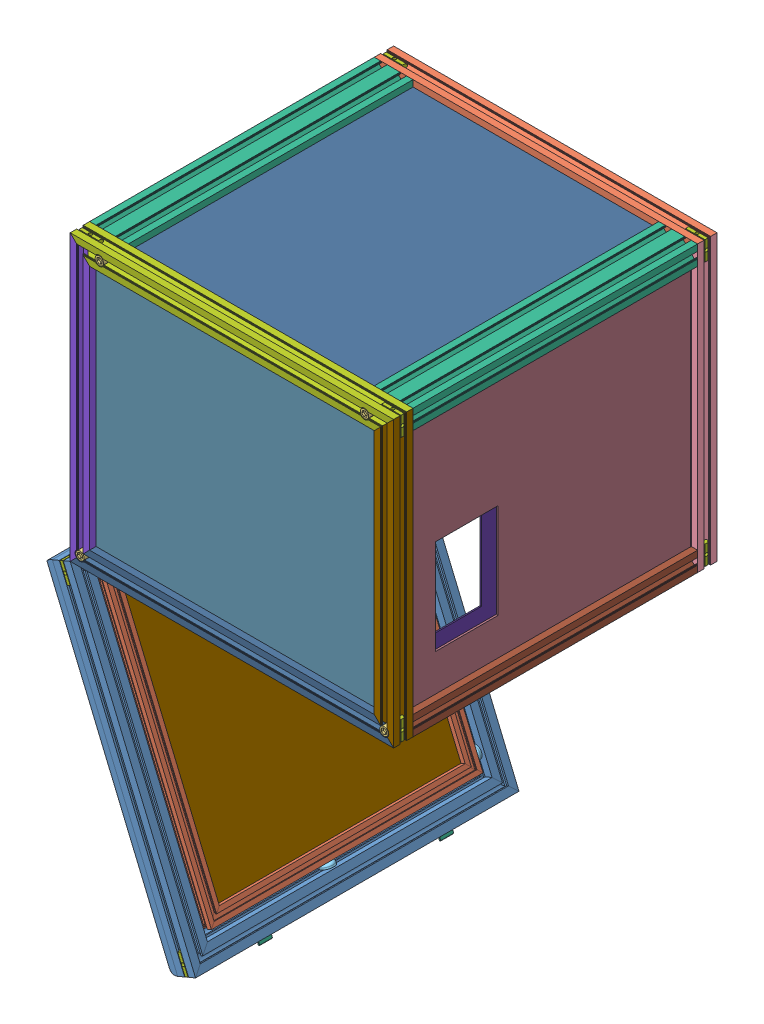
SolidWorks assembly 总装图, configuration 默认. Lengths in mm.
Overall size (555.31 924.17 500).
103 component instances, 37 part files, 0 mates.
Components (placement in the parent):
- Iner box-X3(JL-8-3060E) 500mm-1: Iner box-X3(JL-8-3060E) 500mm [默认] at (-176.4266 -29.8898 -15) x (0 1 0) z (1 0 0) size (60 30 500)
- Iner box-X4(JL-8-3060E) 500mm-1: Iner box-X4(JL-8-3060E) 500mm [默认] at (323.5734 410.1102 -15) x (0 -1 0) z (-1 0 0) size (60 30 500)
- Iner box-Y3(JL-8-3060E) 440mm-1: Iner box-Y3(JL-8-3060E) 440mm [默认] at (-176.4266 410.1102 -15) x (1 0 0) z (0 -1 0) size (60 30 440)
- Iner box-Y4(JL-8-3060E) 440mm-1: Iner box-Y4(JL-8-3060E) 440mm [默认] at (263.5734 410.1102 -15) x (1 0 0) z (0 -1 0) size (60 30 440)
- Iner box-Z1(JL-8-3030E) 440mm-1: Iner box-Z1(JL-8-3030E) 440mm [默认] at (-176.4266 -29.8898 15) size (30 30 440)
- Iner box-Z2(JL-8-6060E) 440mm-1: Iner box-Z2(JL-8-6060E) 440mm [默认] at (-116.4266 380.1102 455) x (-1 0 0) z (0 0 -1) size (60 30 440)
- Iner box-Z2(JL-8-6060E) 440mm-2: Iner box-Z2(JL-8-6060E) 440mm [默认] at (263.5734 380.1102 15) size (60 30 440)
- Iner box-X1(JL-8-3030E)-1: Iner box-X1(JL-8-3030E) [默认] at (-176.4266 410.1102 455) x (0 0 1) z (1 0 0) size (30 30 500)
- Iner box-Y1(JL-8-3030E) 440mm-1: Iner box-Y1(JL-8-3030E) 440mm [默认] at (-176.4266 -29.8898 455) x (0 0 1) z (0 1 0) size (30 30 440)
- Iner box-Y2(JL-8-3030E) 440mm-1: Iner box-Y2(JL-8-3030E) 440mm [默认] at (323.5734 410.1102 455) x (0 0 1) z (0 -1 0) size (30 30 440)
- Iner box-X2(JL-8-3030E)-1: Iner box-X2(JL-8-3030E) [默认] at (323.5734 -29.8898 455) x (0 0 1) z (-1 0 0) size (30 30 500)
- outer box-Z3(JL-8-3030E) 440mm-1: outer box-Z3(JL-8-3030E) 440mm [默认] at (323.5734 0.1102 15) x (-1 0 0) z (0 0 1) size (30 30 440)
- Iner box-X3(JL-6-2020E) 420mm-1: Iner box-X3(JL-6-2020E) 420mm [默认] at (-136.4266 370.1102 445) x (0 -1 0) z (1 0 0) size (20 20 420)
- Iner box-Y1(JL-6-2020E) 400mm-1: Iner box-Y1(JL-6-2020E) 400mm [默认] at (-136.4266 -29.8898 425) x (0 0 1) z (0 1 0) size (20 20 400)
- Iner box-Y2(JL-6-2020E) 400mm-1: Iner box-Y2(JL-6-2020E) 400mm [默认] at (263.5734 -29.8898 425) x (0 0 1) z (0 1 0) size (20 20 400)
- Iner box-X1(JL-6-2020E) 420mm-1: Iner box-X1(JL-6-2020E) 420mm [默认] at (-136.4266 -29.8898 445) x (0 0 -1) z (1 0 0) size (20 20 420)
- Iner box-Z1(JL-6-2020E) 380mm-1: Iner box-Z1(JL-6-2020E) 380mm [默认] at (263.5734 370.1102 425) x (1 0 0) z (0 0 -1) size (20 20 380)
- Iner box-Z1(JL-6-2020E) 380mm-2: Iner box-Z1(JL-6-2020E) 380mm [默认] at (263.5734 -9.8898 425) x (1 0 0) z (0 0 -1) size (20 20 380)
- Iner box-Z1(JL-6-2020E) 380mm-3: Iner box-Z1(JL-6-2020E) 380mm [默认] at (-136.4266 -9.8898 425) x (1 0 0) z (0 0 -1) size (20 20 380)
- Iner box-Z1(JL-6-2020E) 380mm-4: Iner box-Z1(JL-6-2020E) 380mm [默认] at (-116.4266 350.1102 45) x (0 1 0) z (0 0 1) size (20 20 380)
- Iner box-X3(JL-6-2020E) 420mm-2: Iner box-X3(JL-6-2020E) 420mm [默认] at (283.5734 370.1102 25) x (0 -1 0) z (-1 0 0) size (20 20 420)
- Iner box-Y1(JL-6-2020E) 400mm-2: Iner box-Y1(JL-6-2020E) 400mm [默认] at (-136.4266 370.1102 45) x (0 0 -1) z (0 -1 0) size (20 20 400)
- Iner box-Y3(JL-6-2020E) 400mm-1: Iner box-Y3(JL-6-2020E) 400mm [默认] at (283.5734 -29.8898 45) x (0 0 -1) z (0 1 0) size (20 20 400)
- Iner box-X2(JL-6-2020E) 420mm-1: Iner box-X2(JL-6-2020E) 420mm [默认] at (283.5734 -9.8898 45) x (0 0 -1) z (-1 0 0) size (20 20 420)
- outer door(JL-6-6060RG) 500mm-1: outer door(JL-6-6060RG) 500mm [默认] at (17.366 -490.8067 -15) x (-0.387585 0.921834 0) z (0 0 1) size (60 60 500)
- outer door(JL-6-6060RG) 500mm-2: outer door(JL-6-6060RG) 500mm [默认] at (-176.4266 -29.8898 485) x (0.387585 -0.921834 0) z (0 0 -1) size (60 60 500)
- outer door(JL-6-6060RG) 500mm-3: outer door(JL-6-6060RG) 500mm [默认] at (17.366 -490.8067 485) x (0 0 -1) z (-0.387585 0.921834 0) size (60 60 500)
- outer door(JL-6-6060RG) 500mm-4: outer door(JL-6-6060RG) 500mm [默认] at (-176.4266 -29.8898 -15) x (0 0 1) z (0.387585 -0.921834 0) size (60 60 500)
- iner door(JL-6-2020E) 420mm-1: iner door(JL-6-2020E) 420mm [默认] at (-16.5741 -461.6851 25) x (0.921834 0.387585 0) z (0 0 1) size (20 20 420)
- iner door(JL-6-2020E) 420mm-2: iner door(JL-6-2020E) 420mm [默认] at (-179.3599 -74.5148 25) x (0.921834 0.387585 0) z (0.387585 -0.921834 0) size (20 20 420)
- iner door(JL-6-2020E) 420mm-3: iner door(JL-6-2020E) 420mm [默认] at (-16.5741 -461.6851 445) x (0.921834 0.387585 0) z (-0.387585 0.921834 0) size (20 20 420)
- iner door(JL-6-2020E) 420mm-4: iner door(JL-6-2020E) 420mm [默认] at (-179.3599 -74.5148 445) x (0.921834 0.387585 0) z (0 0 -1) size (20 20 420)
- M8-25mm-1: M8-25mm [默认] at (-131.4266 395.1102 477) size (13 13 43)
- M8-25mm-2: M8-25mm [默认] at (278.5734 395.1102 477) x (0.961201 -0.27585 0) z (0 0 1) size (13 13 43)
- M8-25mm-3: M8-25mm [默认] at (278.5734 395.1102 -7) x (0.35329 0.935514 0) z (0 0 -1) size (13 13 43)
- M8-25mm-4: M8-25mm [默认] at (-161.4266 -14.8898 -7) x (0.920892 -0.389817 0) z (0 0 -1) size (13 13 43)
- M8-25mm-5: M8-25mm [默认] at (-161.4266 -14.8898 477) x (-0.304822 0.952409 0) z (0 0 1) size (13 13 43)
- M8-25mm-6: M8-25mm [默认] at (-131.4266 395.1102 -7) x (0.986563 0.163384 0) z (0 0 -1) size (13 13 43)
- M6-25mm-1: M6-25mm [默认] at (-126.4266 -19.8898 439) size (10 10 31)
- M6-25mm-2: M6-25mm [默认] at (-126.4266 360.1102 31) x (0.875472 0.483269 0) z (0 0 -1) size (10 10 31)
- M6-25mm-3: M6-25mm [默认] at (-126.4266 360.1102 439) x (0.902761 0.430142 0) z (0 0 1) size (10 10 31)
- M6-25mm-4: M6-25mm [默认] at (273.5734 360.1102 31) x (0.990077 0.140528 0) z (0 0 -1) size (10 10 31)
- M6-25mm-5: M6-25mm [默认] at (273.5734 360.1102 439) size (10 10 31)
- M6-25mm-6: M6-25mm [默认] at (-126.4266 -19.8898 31) x (-0.813233 0.581938 0) z (0 0 -1) size (10 10 31)
- rubber gasket-1: rubber gasket [默认] at (-131.4266 365.1102 15) x (0.3439 0.939006 0) z (0 0 1) size (20 20 6.75)
- rubber gasket-2: rubber gasket [默认] at (278.5734 365.1102 15) size (20 20 6.75)
- rubber gasket-3: rubber gasket [默认] at (278.5734 15.1102 15) x (-0.779437 0.62648 0) z (0 0 1) size (20 20 6.75)
- rubber gasket-4: rubber gasket [默认] at (-45.1717 -419.4692 440) x (0.359958 -0.856126 0.37078) z (0.921834 0.387585 0) size (20 20 6.75)
- rubber gasket-5: rubber gasket [默认] at (-193.7129 -66.1784 426.8572) x (-0.051642 0.122825 -0.991084) z (0.921834 0.387585 0) size (20 20 6.75)
- rubber gasket-6: rubber gasket [默认] at (-27.7304 -460.9517 30) x (-0.029709 0.070659 -0.997058) z (0.921834 0.387585 0) size (20 20 6.75)
- rubber gasket-7: rubber gasket [默认] at (283.5734 -19.8898 435) x (0 1 0) z (1 0 0) size (20 20 6.75)
- rubber gasket-8: rubber gasket [默认] at (278.5734 380.1102 425) x (1 0 0) z (0 -1 0) size (20 20 6.75)
- rubber gasket-9: rubber gasket [默认] at (-136.4266 -19.8898 35) x (0 1 0) z (-1 0 0) size (20 20 6.75)
- rubber gasket-10: rubber gasket [默认] at (-166.999 -91.0136 15) x (0.598219 -0.801333 0) z (0 0 1) size (20 20 6.75)
- rubber gasket-11: rubber gasket [默认] at (-136.4266 -19.8898 435) x (0 1 0) z (-1 0 0) size (20 20 6.75)
- rubber gasket-12: rubber gasket [默认] at (-131.4266 380.1102 425) x (0 0 -1) z (0 -1 0) size (20 20 6.75)
- rubber gasket-13: rubber gasket [默认] at (-131.4266 380.1102 45) x (1 0 0) z (0 -1 0) size (20 20 6.75)
- rubber gasket-14: rubber gasket [默认] at (278.5734 380.1102 45) x (0 0 -1) z (0 -1 0) size (20 20 6.75)
- rubber gasket-15: rubber gasket [默认] at (-131.4266 15.1102 15) size (20 20 6.75)
- rubber gasket-16: rubber gasket [默认] at (-8.0891 -468.9655 255) x (-0.697013 -0.293059 -0.654437) z (-0.387585 0.921834 0) size (20 20 6.75)
- rubber gasket-17: rubber gasket [默认] at (-186.6403 -82.9998 30) x (-0.141837 0.337346 -0.930634) z (0.921834 0.387585 0) size (20 20 6.75)
- rubber gasket-18: rubber gasket [默认] at (283.5734 -19.8898 35) x (0 1 0) z (1 0 0) size (20 20 6.75)
- rubber gasket-19: rubber gasket [默认] at (-19.7166 -441.3104 15) x (-0.644071 0.764966 0) z (0 0 1) size (20 20 6.75)
- rubber gasket-20: rubber gasket [默认] at (-178.6266 -63.3586 255) x (0.610646 0.256746 -0.749128) z (0.387585 -0.921834 0) size (20 20 6.75)
- rubber gasket-21: rubber gasket [默认] at (-93.3578 -266.162 455) x (-0.680464 -0.732781 0) z (0 0 -1) size (20 20 6.75)
- _X2_950194A9_X0_-1: _X2_950194A9_X0_ [默认] at (-1.3473 -498.6747 385) x (0.921834 0.387585 0) z (0 0 -1) size (17 6.45 20)
- _X2_950194A9_X0_-2: _X2_950194A9_X0_ [默认] at (-1.3473 -498.6747 105) x (0.921834 0.387585 0) z (0 0 -1) size (17 6.45 20)
- _X2_89D269FD8FDE63A54EF6_X0_-1: _X2_89D269FD8FDE63A54EF6_X0_ [默认] at (-175.2266 -28.6898 475) x (0 1 0) z (0 0 -1) size (30 30 10)
- _X2_89D269FD8FDE63A54EF6_X0_-2: _X2_89D269FD8FDE63A54EF6_X0_ [默认] at (322.3734 -28.6898 5) x (-1 0 0) z (0 0 -1) size (30 30 10)
- _X2_89D269FD8FDE63A54EF6_X0_-3: _X2_89D269FD8FDE63A54EF6_X0_ [默认] at (-185.645 -33.7656 485) x (0 0 -1) z (-0.921834 -0.387585 0) size (30 30 10)
- _X2_89D269FD8FDE63A54EF6_X0_-4: _X2_89D269FD8FDE63A54EF6_X0_ [默认] at (-175.2266 408.9102 -5) x (0 -1 0) z (0 0 1) size (30 30 10)
- _X2_89D269FD8FDE63A54EF6_X0_-5: _X2_89D269FD8FDE63A54EF6_X0_ [默认] at (8.1476 -494.6826 -15) x (0 0 1) z (-0.921834 -0.387585 0) size (30 30 10)
- _X2_89D269FD8FDE63A54EF6_X0_-6: _X2_89D269FD8FDE63A54EF6_X0_ [默认] at (-175.2266 -28.6898 5) x (0 1 0) z (0 0 -1) size (30 30 10)
- _X2_89D269FD8FDE63A54EF6_X0_-7: _X2_89D269FD8FDE63A54EF6_X0_ [默认] at (-185.645 -33.7656 -15) x (0.387585 -0.921834 0) z (-0.921834 -0.387585 0) size (30 30 10)
- _X2_89D269FD8FDE63A54EF6_X0_-8: _X2_89D269FD8FDE63A54EF6_X0_ [默认] at (-1.0707 -498.5584 485) x (0 0 -1) z (0.921834 0.387585 0) size (30 30 10)
- _X2_89D269FD8FDE63A54EF6_X0_-9: _X2_89D269FD8FDE63A54EF6_X0_ [默认] at (-175.2266 408.9102 465) x (0 -1 0) z (0 0 1) size (30 30 10)
- _X2_89D269FD8FDE63A54EF6_X0_-10: _X2_89D269FD8FDE63A54EF6_X0_ [默认] at (322.3734 408.9102 -5) x (-1 0 0) z (0 0 1) size (30 30 10)
- _X2_89D269FD8FDE63A54EF6_X0_-11: _X2_89D269FD8FDE63A54EF6_X0_ [默认] at (322.3734 408.9102 465) x (-1 0 0) z (0 0 1) size (30 30 10)
- _X2_89D269FD8FDE63A54EF6_X0_-12: _X2_89D269FD8FDE63A54EF6_X0_ [默认] at (322.3734 -28.6898 465) x (0 1 0) z (0 0 1) size (30 30 10)
- _X2_94DD677F_X0_ Big-Door-1: _X2_94DD677F_X0_ Big-Door [默认] at (-43.3557 -471.0185 443.2238) x (0 0 -1) z (0.921834 0.387585 0) size (394 394 3)
- _X2_94DD677F_X0_ Small-Door-1: _X2_94DD677F_X0_ Small-Door [默认] at (-12.7369 -442.1726 429.5) x (0 0 -1) z (0.921834 0.387585 0) size (388 388 2)
- _X2_94DD677F_X0_ Big-Back-1: _X2_94DD677F_X0_ Big-Back [默认] at (272.7734 396.2102 459.8) x (0 0 -1) z (0 1 0) size (454 394 3)
- _X2_94DD677F_X0_ Big-Bottom-1: _X2_94DD677F_X0_ Big-Bottom [默认] at (-121.2266 354.9102 -1.1) x (1 0 0) z (0 0 -1) size (394 334 3)
- _X2_94DD677F_X0_ Big-Left-1: _X2_94DD677F_X0_ Big-Left [默认] at (-162.5266 -9.0898 10.2) x (0 0 1) z (-1 0 0) size (454 394 3)
- _X2_94DD677F_X0_ Big-Right-1: _X2_94DD677F_X0_ Big-Right [默认] at (307.4734 -9.0898 10.2) x (0 0 1) z (-1 0 0) size (454 394 3)
- _X2_94DD677F_X0_ Big-Top-1: _X2_94DD677F_X0_ Big-Top [默认] at (-155.6266 384.9102 468.9) x (1 0 0) z (0 0 -1) size (454 394 3)
- _X2_94DD677F_X0_ Small-Back-1: _X2_94DD677F_X0_ Small-Back [默认] at (-119.9266 359.0102 41.5) x (1 0 0) z (0 -1 0) size (388 388 2)
- _X2_94DD677F_X0_ Small-Bottom-1: _X2_94DD677F_X0_ Small-Bottom [默认] at (-119.9266 -14.3898 438.1) x (0 1 0) z (0 0 -1) size (368 388 2)
- _X2_94DD677F_X0_ Small-Left-1: _X2_94DD677F_X0_ Small-Left [默认] at (276.6734 354.6102 40.5) x (0 -1 0) z (-1 0 0) size (368 388 2)
- _X2_94DD677F_X0_ Small-Right-1: _X2_94DD677F_X0_ Small-Right [默认] at (-123.3266 -14.3898 429.5) x (0 1 0) z (-1 0 0) size (368 388 2)
- _X2_94DD677F_X0_ Small-Bottom-2: _X2_94DD677F_X0_ Small-Bottom [默认] at (267.0734 354.6102 33.9) x (0 -1 0) z (0 0 -1) size (368 388 2)
- M6-25mm-7: M6-25mm [默认] at (273.5734 -19.8898 439) size (10 10 31)
- M6-25mm-8: M6-25mm [默认] at (273.5734 -19.8898 31) x (0.590399 -0.807111 0) z (0 0 -1) size (10 10 31)
- M8-25mm-7: M8-25mm [默认] at (308.5734 -14.8898 -7) x (1 0 0) z (0 0 -1) size (13 13 43)
- M8-25mm-8: M8-25mm [默认] at (308.5734 -14.8898 477) size (13 13 43)
- 2020_X2_89D24EF6_X0_-1: 2020_X2_89D24EF6_X0_ [默认] at (-136.4266 365.1102 31.9) size (20 20 6)
- 2020_X2_89D24EF6_X0_-2: 2020_X2_89D24EF6_X0_ [默认] at (283.5734 365.1102 38.1) x (-1 0 0) z (0 0 -1) size (20 20 6)
- 2020_X2_89D24EF6_X0_-3: 2020_X2_89D24EF6_X0_ [默认] at (278.5734 -29.8898 38.1) x (0 1 0) z (0 0 -1) size (20 20 6)
- 2020_X2_89D24EF6_X0_-4: 2020_X2_89D24EF6_X0_ [默认] at (278.5734 -29.8898 438.1) x (0 1 0) z (0 0 -1) size (20 20 6)
- 2020_X2_89D24EF6_X0_-5: 2020_X2_89D24EF6_X0_ [默认] at (-136.4266 -24.8898 38.1) x (1 0 0) z (0 0 -1) size (20 20 6)
- 2020_X2_89D24EF6_X0_-6: 2020_X2_89D24EF6_X0_ [默认] at (278.5734 370.1102 431.9) x (0 -1 0) z (0 0 1) size (20 20 6)
- 2020_X2_89D24EF6_X0_-7: 2020_X2_89D24EF6_X0_ [默认] at (-136.4266 -24.8898 438.1) x (1 0 0) z (0 0 -1) size (20 20 6)
- 2020_X2_89D24EF6_X0_-8: 2020_X2_89D24EF6_X0_ [默认] at (-136.4266 365.1102 431.9) size (20 20 6)
